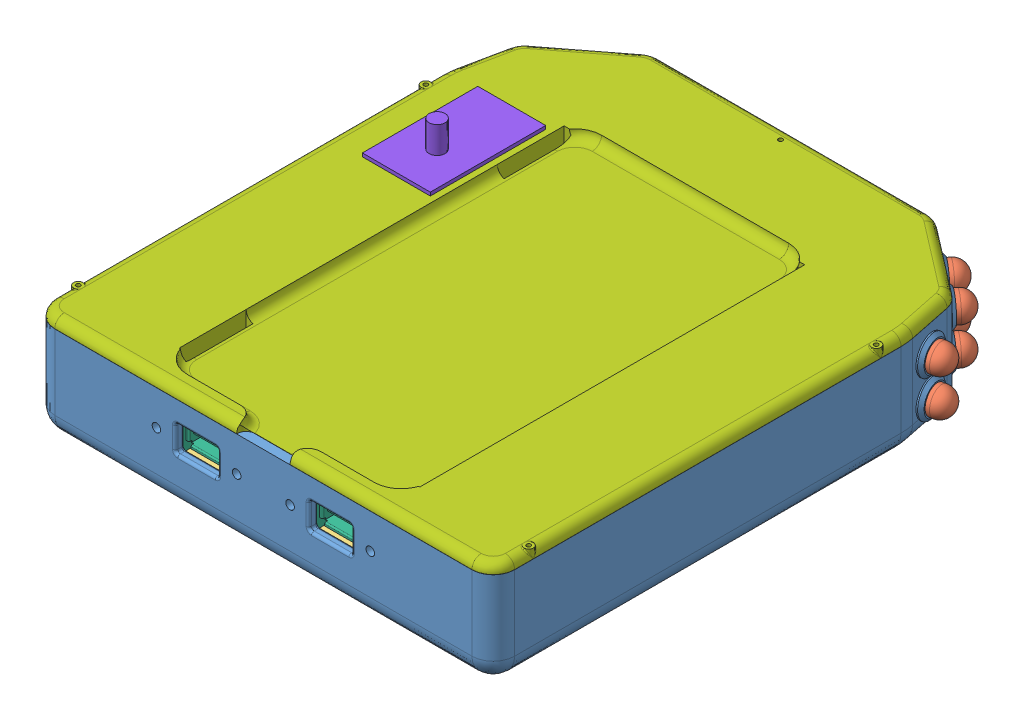
SolidWorks assembly Assem1, configuration Default. Lengths in mm.
Overall size (186.2 50.77 206.63).
32 component instances, 8 part files, 66 mates.
Components (placement in the parent):
- enclosure bottom-1: enclosure bottom [Default] at (-0.9732 -28.2293 19.6921) size (173.31 36 200.23)
- 10mm LED-2: 10mm LED [Default] at (-16.2549 -2.2293 -95.7851) x (1 0 0) z (0 1 0) size (10.8 18.65 10.8)
- breadboard-1: breadboard [Default] at (-0.9732 -15.2293 17.8921) size (152.4 1.57 152.4)
- 10mm LED-3: 10mm LED [Default] at (-16.2549 -16.2293 -95.7851) x (1 0 0) z (0 1 0) size (10.8 18.65 10.8)
- 10mm LED-4: 10mm LED [Default] at (-30.2549 -16.2293 -95.7851) x (1 0 0) z (0 1 0) size (10.8 18.65 10.8)
- 10mm LED-5: 10mm LED [Default] at (-30.2549 -2.2293 -95.7851) x (1 0 0) z (0 1 0) size (10.8 18.65 10.8)
- 10mm LED-6: 10mm LED [Default] at (-44.2549 -16.2293 -95.7851) x (1 0 0) z (0 1 0) size (10.8 18.65 10.8)
- 10mm LED-7: 10mm LED [Default] at (-44.2549 -2.2293 -95.7851) x (1 0 0) z (0 1 0) size (10.8 18.65 10.8)
- 10mm LED-8: 10mm LED [Default] at (-58.3289 -2.2293 -91.0029) x (0.745166 0.34202 -0.572494) z (-0.271218 0.939693 0.208371) size (10.8 18.65 10.8)
- 10mm LED-9: 10mm LED [Default] at (-58.3289 -16.2293 -91.0029) x (0.745166 0.34202 -0.572494) z (-0.271218 0.939693 0.208371) size (10.8 18.65 10.8)
- 10mm LED-10: 10mm LED [Default] at (-69.4308 -2.2293 -82.4736) x (0.745166 0.34202 -0.572494) z (-0.271218 0.939693 0.208371) size (10.8 18.65 10.8)
- 10mm LED-11: 10mm LED [Default] at (-69.4308 -16.2293 -82.4736) x (0.745166 0.34202 -0.572494) z (-0.271218 0.939693 0.208371) size (10.8 18.65 10.8)
- 10mm LED-12: 10mm LED [Default] at (-79.4135 -2.2293 -67.2123) x (0.040958 0.979307 -0.198194) z (-0.198194 0.202381 0.959042) size (10.8 18.65 10.8)
- 10mm LED-13: 10mm LED [Default] at (-79.4135 -16.2293 -67.2123) x (0.040958 0.979307 -0.198194) z (-0.198194 0.202381 0.959042) size (10.8 18.65 10.8)
- 10mm LED-14: 10mm LED [Default] at (14.3085 -2.2293 -95.7851) x (1 0 0) z (0 1 0) size (10.8 18.65 10.8)
- 10mm LED-15: 10mm LED [Default] at (14.3085 -16.2293 -95.7851) x (1 0 0) z (0 1 0) size (10.8 18.65 10.8)
- 10mm LED-16: 10mm LED [Default] at (28.3085 -16.2293 -95.7851) x (1 0 0) z (0 1 0) size (10.8 18.65 10.8)
- 10mm LED-17: 10mm LED [Default] at (42.3085 -2.2293 -95.7851) x (1 0 0) z (0 1 0) size (10.8 18.65 10.8)
- 10mm LED-18: 10mm LED [Default] at (28.3085 -2.2293 -95.7851) x (1 0 0) z (0 1 0) size (10.8 18.65 10.8)
- 10mm LED-19: 10mm LED [Default] at (42.3085 -16.2293 -95.7851) x (1 0 0) z (0 1 0) size (10.8 18.65 10.8)
- 10mm LED-20: 10mm LED [Default] at (56.3825 -2.2293 -91.0029) x (0.745166 -0.34202 0.572494) z (0.271218 0.939693 0.208371) size (10.8 18.65 10.8)
- 10mm LED-21: 10mm LED [Default] at (77.467 -2.2293 -67.2123) x (0.040958 -0.979307 0.198194) z (0.198194 0.202381 0.959042) size (10.8 18.65 10.8)
- 10mm LED-22: 10mm LED [Default] at (77.467 -16.2293 -67.2123) x (0.040958 -0.979307 0.198194) z (0.198194 0.202381 0.959042) size (10.8 18.65 10.8)
- 10mm LED-23: 10mm LED [Default] at (56.3825 -16.2293 -91.0029) x (0.745166 -0.34202 0.572494) z (0.271218 0.939693 0.208371) size (10.8 18.65 10.8)
- 10mm LED-24: 10mm LED [Default] at (67.4843 -16.2293 -82.4736) x (0.745166 -0.34202 0.572494) z (0.271218 0.939693 0.208371) size (10.8 18.65 10.8)
- 10mm LED-25: 10mm LED [Default] at (67.4843 -2.2293 -82.4736) x (0.745166 -0.34202 0.572494) z (0.271218 0.939693 0.208371) size (10.8 18.65 10.8)
- Maxbotix sonar-1: Maxbotix sonar [Default] at (-1.9032 -3.4693 -85.7851) size (19.9 22.1 24.88)
- 5mm LED-1: 5mm LED [Default] at (-0.9732 -17.4793 -83.7851) x (-1 0 0) z (0 -1 0) size (5.4 11.83 5.4)
- UPMA-LEADS-1: UPMA-LEADS [Default] at (24.0268 -5.2293 1.0921) x (0 0 -1) z (1 0 0) size (37.5 14.8 38)
- UPMA-LEADS-2: UPMA-LEADS [Default] at (-25.9732 -5.2293 1.0921) x (0 0 -1) z (1 0 0) size (37.5 14.8 38)
- enclosure top-1: enclosure top [Default] at (-1.0232 4.2707 19.6421) size (172 7 198.48)
- missile switch-1: missile switch [Default] at (-61.0232 -15.3993 -27.8351) size (25.4 45.56 43.18)
Mates (geometry in assembly coordinates):
- Concentric1: concentric anti-aligned: cylinder of enclosure bottom-1 through (-16.2549 -2.2293 -81.2851) axis (0 0 -1) radius 5; cylinder of 10mm LED-2 through (-16.2549 -2.2293 -95.7851) axis (0 0 1) radius 5
- Coincident1: coincident anti-aligned: plane of enclosure bottom-1 through (-10.9732 -280.9911 -97.7851) normal (0 0 1); plane of 10mm LED-2 through (-10.8549 -2.2293 -97.7851) normal (0 0 -1)
- Concentric2: concentric anti-aligned: cylinder of enclosure bottom-1 through (-16.2549 -16.2293 -81.2851) axis (0 0 -1) radius 5; cylinder of 10mm LED-3 through (-16.2549 -16.2293 -95.7851) axis (0 0 1) radius 5
- Coincident4: coincident anti-aligned: plane of enclosure bottom-1 through (-10.9732 -280.9911 -97.7851) normal (0 0 1); plane of 10mm LED-3 through (-10.8549 -16.2293 -97.7851) normal (0 0 -1)
- Concentric3: concentric anti-aligned: cylinder of enclosure bottom-1 through (-30.2549 -16.2293 -81.2851) axis (0 0 -1) radius 5; cylinder of 10mm LED-4 through (-30.2549 -16.2293 -95.7851) axis (0 0 1) radius 5
- Coincident5: coincident anti-aligned: plane of enclosure bottom-1 through (-10.9732 -280.9911 -97.7851) normal (0 0 1); plane of 10mm LED-4 through (-24.8549 -16.2293 -97.7851) normal (0 0 -1)
- Concentric4: concentric anti-aligned: cylinder of enclosure bottom-1 through (-30.2549 -2.2293 -81.2851) axis (0 0 -1) radius 5; cylinder of 10mm LED-5 through (-30.2549 -2.2293 -95.7851) axis (0 0 1) radius 5
- Coincident6: coincident anti-aligned: plane of enclosure bottom-1 through (-10.9732 -280.9911 -97.7851) normal (0 0 1); plane of 10mm LED-5 through (-24.8549 -2.2293 -97.7851) normal (0 0 -1)
- Concentric5: concentric anti-aligned: cylinder of enclosure bottom-1 through (-44.2549 -16.2293 -81.2851) axis (0 0 -1) radius 5; cylinder of 10mm LED-6 through (-44.2549 -16.2293 -95.7851) axis (0 0 1) radius 5
- Coincident7: coincident anti-aligned: plane of enclosure bottom-1 through (-10.9732 -280.9911 -97.7851) normal (0 0 1); plane of 10mm LED-6 through (-38.8549 -16.2293 -97.7851) normal (0 0 -1)
- Concentric6: concentric anti-aligned: cylinder of enclosure bottom-1 through (-44.2549 -2.2293 -81.2851) axis (0 0 -1) radius 5; cylinder of 10mm LED-7 through (-44.2549 -2.2293 -95.7851) axis (0 0 1) radius 5
- Coincident8: coincident anti-aligned: plane of enclosure bottom-1 through (-10.9732 -280.9911 -97.7851) normal (0 0 1); plane of 10mm LED-7 through (-38.8549 -2.2293 -97.7851) normal (0 0 -1)
- Concentric7: concentric anti-aligned: cylinder of enclosure bottom-1 through (-55.5874 -2.2293 -87.4345) axis (-0.609236 0 -0.792989) radius 5; cylinder of 10mm LED-8 through (-58.3289 -2.2293 -91.0029) axis (0.609236 0 0.792989) radius 5
- Coincident9: coincident anti-aligned: plane of enclosure bottom-1 through (-53.9965 -280.9911 -96.8536) normal (0.609236 0 0.792989); plane of 10mm LED-8 through (-55.5235 -0.3824 -95.6804) normal (-0.609236 0 -0.792989)
- Concentric8: concentric anti-aligned: cylinder of enclosure bottom-1 through (-55.5874 -16.2293 -87.4345) axis (-0.609236 0 -0.792989) radius 5; cylinder of 10mm LED-9 through (-58.3289 -16.2293 -91.0029) axis (0.609236 0 0.792989) radius 5
- Coincident10: coincident anti-aligned: plane of enclosure bottom-1 through (-53.9965 -280.9911 -96.8536) normal (0.609236 0 0.792989); plane of 10mm LED-9 through (-55.5235 -14.3824 -95.6804) normal (-0.609236 0 -0.792989)
- Concentric9: concentric anti-aligned: cylinder of enclosure bottom-1 through (-66.6892 -2.2293 -78.9052) axis (-0.609236 0 -0.792989) radius 5; cylinder of 10mm LED-10 through (-69.4308 -2.2293 -82.4736) axis (0.609236 0 0.792989) radius 5
- Coincident11: coincident anti-aligned: plane of enclosure bottom-1 through (-53.9965 -280.9911 -96.8536) normal (0.609236 0 0.792989); plane of 10mm LED-10 through (-66.6254 -0.3824 -87.1511) normal (-0.609236 0 -0.792989)
- Concentric10: concentric anti-aligned: cylinder of enclosure bottom-1 through (-66.6892 -16.2293 -78.9052) axis (-0.609236 0 -0.792989) radius 5; cylinder of 10mm LED-11 through (-69.4308 -16.2293 -82.4736) axis (0.609236 0 0.792989) radius 5
- Coincident12: coincident anti-aligned: plane of enclosure bottom-1 through (-53.9965 -280.9911 -96.8536) normal (0.609236 0 0.792989); plane of 10mm LED-11 through (-66.6254 -14.3824 -87.1511) normal (-0.609236 0 -0.792989)
- Concentric11: concentric anti-aligned: cylinder of enclosure bottom-1 through (-75.0066 -2.2293 -66.3016) axis (-0.979307 0 -0.202381) radius 5; cylinder of 10mm LED-12 through (-79.4135 -2.2293 -67.2123) axis (0.979307 0 0.202381) radius 5
- Coincident13: coincident anti-aligned: plane of enclosure bottom-1 through (-79.6952 -280.9911 -75.7315) normal (0.979307 0 0.202381); plane of 10mm LED-12 through (-81.1509 3.0589 -68.6873) normal (-0.979307 0 -0.202381)
- Concentric12: concentric anti-aligned: cylinder of enclosure bottom-1 through (-75.0066 -16.2293 -66.3016) axis (-0.979307 0 -0.202381) radius 5; cylinder of 10mm LED-13 through (-79.4135 -16.2293 -67.2123) axis (0.979307 0 0.202381) radius 5
- Coincident14: coincident anti-aligned: plane of enclosure bottom-1 through (-79.6952 -280.9911 -75.7315) normal (0.979307 0 0.202381); plane of 10mm LED-13 through (-81.1509 -10.9411 -68.6873) normal (-0.979307 0 -0.202381)
- Concentric13: concentric anti-aligned: cylinder of enclosure bottom-1 through (14.3085 -2.2293 -81.2851) axis (0 0 -1) radius 5; cylinder of 10mm LED-14 through (14.3085 -2.2293 -95.7851) axis (0 0 1) radius 5
- Coincident15: coincident anti-aligned: plane of enclosure bottom-1 through (49.3085 -280.9911 -97.7851) normal (0 0 1); plane of 10mm LED-14 through (19.7085 -2.2293 -97.7851) normal (0 0 -1)
- Concentric14: concentric anti-aligned: cylinder of enclosure bottom-1 through (14.3085 -16.2293 -81.2851) axis (0 0 -1) radius 5; cylinder of 10mm LED-15 through (14.3085 -16.2293 -95.7851) axis (0 0 1) radius 5
- Coincident16: coincident anti-aligned: plane of enclosure bottom-1 through (49.3085 -280.9911 -97.7851) normal (0 0 1); plane of 10mm LED-15 through (19.7085 -16.2293 -97.7851) normal (0 0 -1)
- Concentric15: concentric anti-aligned: cylinder of enclosure bottom-1 through (28.3085 -2.2293 -81.2851) axis (0 0 -1) radius 5; cylinder of 10mm LED-18 through (28.3085 -2.2293 -95.7851) axis (0 0 1) radius 5
- Concentric16: concentric anti-aligned: cylinder of enclosure bottom-1 through (28.3085 -16.2293 -81.2851) axis (0 0 -1) radius 5; cylinder of 10mm LED-16 through (28.3085 -16.2293 -95.7851) axis (0 0 1) radius 5
- Concentric17: concentric anti-aligned: cylinder of enclosure bottom-1 through (42.3085 -2.2293 -81.2851) axis (0 0 -1) radius 5; cylinder of 10mm LED-17 through (42.3085 -2.2293 -95.7851) axis (0 0 1) radius 5
- Concentric18: concentric anti-aligned: cylinder of enclosure bottom-1 through (42.3085 -16.2293 -81.2851) axis (0 0 -1) radius 5; cylinder of 10mm LED-19 through (42.3085 -16.2293 -95.7851) axis (0 0 1) radius 5
- Coincident17: coincident anti-aligned: plane of enclosure bottom-1 through (49.3085 -280.9911 -97.7851) normal (0 0 1); plane of 10mm LED-17 through (47.7085 -2.2293 -97.7851) normal (0 0 -1)
- Coincident18: coincident anti-aligned: plane of enclosure bottom-1 through (49.3085 -280.9911 -97.7851) normal (0 0 1); plane of 10mm LED-18 through (33.7085 -2.2293 -97.7851) normal (0 0 -1)
- Coincident19: coincident anti-aligned: plane of enclosure bottom-1 through (49.3085 -280.9911 -97.7851) normal (0 0 1); plane of 10mm LED-16 through (33.7085 -16.2293 -97.7851) normal (0 0 -1)
- Coincident20: coincident anti-aligned: plane of enclosure bottom-1 through (49.3085 -280.9911 -97.7851) normal (0 0 1); plane of 10mm LED-19 through (47.7085 -16.2293 -97.7851) normal (0 0 -1)
- Concentric19: concentric anti-aligned: cylinder of enclosure bottom-1 through (53.6409 -16.2293 -87.4345) axis (0.609236 0 -0.792989) radius 5; cylinder of 10mm LED-23 through (56.3825 -16.2293 -91.0029) axis (-0.609236 0 0.792989) radius 5
- Concentric20: concentric anti-aligned: cylinder of enclosure bottom-1 through (53.6409 -2.2293 -87.4345) axis (0.609236 0 -0.792989) radius 5; cylinder of 10mm LED-20 through (56.3825 -2.2293 -91.0029) axis (-0.609236 0 0.792989) radius 5
- Concentric21: concentric anti-aligned: cylinder of enclosure bottom-1 through (64.7428 -16.2293 -78.9052) axis (0.609236 0 -0.792989) radius 5; cylinder of 10mm LED-24 through (67.4843 -16.2293 -82.4736) axis (-0.609236 0 0.792989) radius 5
- Concentric22: concentric anti-aligned: cylinder of enclosure bottom-1 through (64.7428 -2.2293 -78.9052) axis (0.609236 0 -0.792989) radius 5; cylinder of 10mm LED-25 through (67.4843 -2.2293 -82.4736) axis (-0.609236 0 0.792989) radius 5
- Concentric23: concentric anti-aligned: cylinder of enclosure bottom-1 through (73.0602 -16.2293 -66.3016) axis (0.979307 0 -0.202381) radius 5; cylinder of 10mm LED-22 through (77.467 -16.2293 -67.2123) axis (-0.979307 0 0.202381) radius 5
- Concentric24: concentric anti-aligned: cylinder of enclosure bottom-1 through (73.0602 -2.2293 -66.3016) axis (0.979307 0 -0.202381) radius 5; cylinder of 10mm LED-21 through (77.467 -2.2293 -67.2123) axis (-0.979307 0 0.202381) radius 5
- Coincident21: coincident anti-aligned: plane of enclosure bottom-1 through (76.0834 -280.9911 -78.3892) normal (-0.609236 0 0.792989); plane of 10mm LED-20 through (61.6248 -4.0762 -89.4974) normal (0.609236 0 -0.792989)
- Coincident22: coincident anti-aligned: plane of enclosure bottom-1 through (76.0834 -280.9911 -78.3892) normal (-0.609236 0 0.792989); plane of 10mm LED-25 through (72.7267 -4.0762 -80.9681) normal (0.609236 0 -0.792989)
- Coincident23: coincident anti-aligned: plane of enclosure bottom-1 through (76.0834 -280.9911 -78.3892) normal (-0.609236 0 0.792989); plane of 10mm LED-24 through (72.7267 -18.0762 -80.9681) normal (0.609236 0 -0.792989)
- Coincident24: coincident anti-aligned: plane of enclosure bottom-1 through (76.0834 -280.9911 -78.3892) normal (-0.609236 0 0.792989); plane of 10mm LED-23 through (61.6248 -18.0762 -89.4974) normal (0.609236 0 -0.792989)
- Coincident25: coincident anti-aligned: plane of enclosure bottom-1 through (81.1026 -280.9911 -59.5027) normal (-0.979307 0 0.202381); plane of 10mm LED-21 through (79.6468 -7.5176 -66.5469) normal (0.979307 0 -0.202381)
- Coincident26: coincident anti-aligned: plane of enclosure bottom-1 through (81.1026 -280.9911 -59.5027) normal (-0.979307 0 0.202381); plane of 10mm LED-22 through (79.6468 -21.5176 -66.5469) normal (0.979307 0 -0.202381)
- Concentric25: concentric anti-aligned: cylinder of enclosure bottom-1 through (-0.9732 -3.4793 -81.2851) axis (0 0 -1) radius 8.25; cylinder of Maxbotix sonar-1 through (-0.9732 -3.4793 -99.7043) axis (0 0 1) radius 8.2
- Coincident27: coincident anti-aligned: plane of enclosure bottom-1 through (9.0268 -280.9911 -85.7851) normal (0 0 1); plane of Maxbotix sonar-1 through (-1.9032 -3.4693 -85.7851) normal (0 0 -1)
- Parallel1: parallel aligned: plane of enclosure bottom-1 through (-0.9732 7.7707 19.6921) normal (0 1 0); plane of Maxbotix sonar-1 through (-11.8532 7.5807 -84.1851) normal (0 1 0)
- Concentric26: concentric anti-aligned: cylinder of enclosure bottom-1 through (-0.9732 -17.4793 -81.2851) axis (0 0 -1) radius 2.5; cylinder of 5mm LED-1 through (-0.9732 -17.4793 -83.7851) axis (0 0 1) radius 2.5
- Coincident29: coincident anti-aligned: plane of enclosure bottom-1 through (9.0268 -280.9911 -85.7851) normal (0 0 1); plane of 5mm LED-1 through (-3.6732 -17.4793 -85.7851) normal (0 0 -1)
- Parallel2: parallel aligned: plane of enclosure bottom-1 through (-0.9732 7.7707 19.6921) normal (0 1 0); plane of 5mm LED-1 through (-1.7432 -17.3043 -88.7851) normal (0 1 0)
- Concentric27: concentric anti-aligned: cylinder of enclosure bottom-1 through (39.0268 -5.2293 -103.0361) axis (0 0 1) radius 1.6; cylinder of UPMA-LEADS-1 through (39.0268 -5.2293 93.6922) axis (0 0 -1) radius 1.5875
- Concentric28: concentric anti-aligned: cylinder of enclosure bottom-1 through (9.0268 -5.2293 -103.0361) axis (0 0 1) radius 1.6; cylinder of UPMA-LEADS-1 through (9.0268 -5.2293 93.6922) axis (0 0 -1) radius 1.5875
- Coincident30: coincident anti-aligned: plane of enclosure bottom-1 through (-78.9732 -280.9911 93.6921) normal (0 0 -1); plane of UPMA-LEADS-1 through (12.0768 -12.2293 93.6921) normal (0 0 1)
- Concentric29: concentric anti-aligned: cylinder of enclosure bottom-1 through (-10.9732 -5.2293 -103.0361) axis (0 0 1) radius 1.6; cylinder of UPMA-LEADS-2 through (-10.9732 -5.2293 93.6922) axis (0 0 -1) radius 1.5875
- Concentric30: concentric anti-aligned: cylinder of enclosure bottom-1 through (-40.9732 -5.2293 -103.0361) axis (0 0 1) radius 1.6; cylinder of UPMA-LEADS-2 through (-40.9732 -5.2293 93.6922) axis (0 0 -1) radius 1.5875
- Coincident31: coincident anti-aligned: plane of enclosure bottom-1 through (-78.9732 -280.9911 93.6921) normal (0 0 -1); plane of UPMA-LEADS-2 through (-37.9232 -12.2293 93.6921) normal (0 0 1)
- Concentric31: concentric anti-aligned: cylinder of enclosure top-1 through (-61.0232 4.2707 -27.8351) axis (0 1 0) radius 6; cylinder of missile switch-1 through (-61.0232 11.2707 -27.8351) axis (0 -1 0) radius 6
- Coincident32: coincident anti-aligned: plane of enclosure top-1 through (-1.0232 11.2707 19.6421) normal (0 1 0); plane of missile switch-1 through (-61.0232 11.2707 -27.8351) normal (0 -1 0)
- Parallel3: parallel aligned: plane of enclosure top-1 through (-41.3049 7.7707 -77.7851) normal (0 0 -1); plane of missile switch-1 through (-48.3232 12.5407 -55.7751) normal (0 0 -1)
- Concentric32: concentric anti-aligned: cylinder of enclosure bottom-1 through (72.8268 -22.2293 -33.8079) axis (0 1 0) radius 0.8; cylinder of breadboard-1 through (72.8268 -13.6545 -33.8079) axis (0 -1 0) radius 1.2
- Parallel4: parallel aligned: plane of enclosure bottom-1 through (-76.7232 -15.2293 93.6921) normal (-1 0 0); plane of breadboard-1 through (-77.1732 -13.6545 94.0921) normal (-1 0 0)
- Coincident34: coincident anti-aligned: plane of enclosure bottom-1 through (-0.9732 -15.2293 19.6921) normal (0 1 0); plane of breadboard-1 through (-0.9732 -15.2293 17.8921) normal (0 -1 0)
